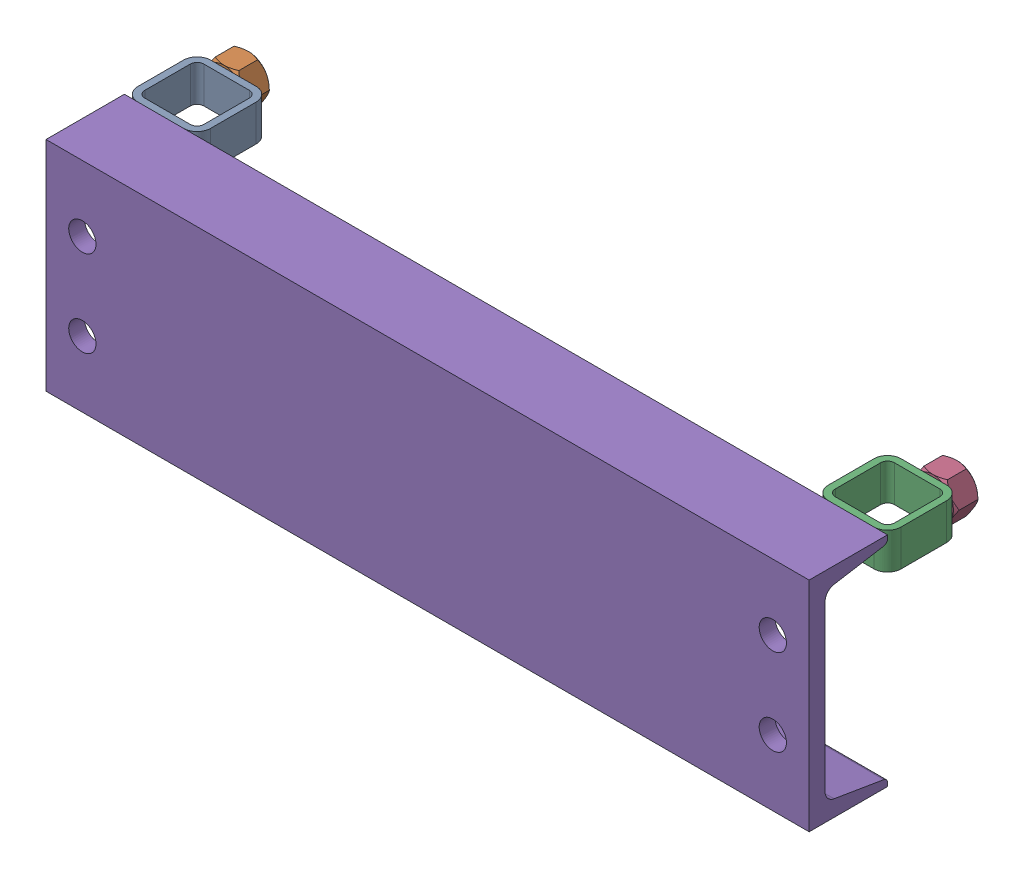
SolidWorks assembly 01-016-00-0, configuration Default. Lengths in mm.
Overall size (533.4 153.99 122.48).
7 component instances, 3 part files, 0 mates.
Components (placement in the parent):
- 01-005-00-0-8-1: 01-005-00-0-8 [Default] at (-215.9 63.5 -27.3939) x (0 0 -1) z (0 1 0) size (67.69 50.8 28.57)
  - tube square_ai(PreviewCfg)-1: tube square_ai(PreviewCfg) [Default] at origin size (50.8 50.8 25.4)
  - hex nut_ai(HNUT 0.7500-10-D-C)-1: hex nut_ai(HNUT 0.7500-10-D-C) [Default] at (67.691 31.75 0) x (0 0 -1) z (1 0 0) size (28.57 33 16.89)
- 01-005-00-0-9-1: 01-005-00-0-9 [Default] at (215.9 63.5 -27.3939) x (0 0 -1) z (0 -1 0) size (67.69 50.8 28.57)
  - tube square_ai(PreviewCfg)-1: tube square_ai(PreviewCfg) [Default] at origin size (50.8 50.8 25.4)
  - hex nut_ai(HNUT 0.7500-10-D-C)-1: hex nut_ai(HNUT 0.7500-10-D-C) [Default] at (67.691 31.75 0) x (0 0 -1) z (1 0 0) size (28.57 33 16.89)
- 01-014-00-0-1: 01-014-00-0 [Default] at origin size (533.4 152.4 54.79)
